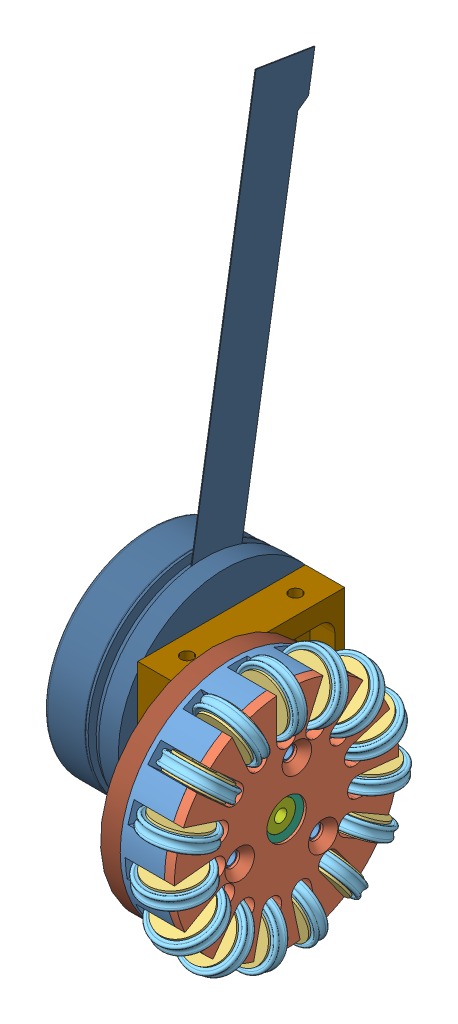
SolidWorks assembly drive_left, configuration Default. Lengths in mm.
Overall size (58.89 137.4 77.93).
70 component instances, 12 part files, 26 mates.
Components (placement in the parent):
- wheel_hub_flat_back-1: wheel_hub_flat_back [Default] at (-31.4027 -2.3485 15.5279) size (9 45.5 45.5)
- wheel_cover-1: wheel_cover [Default] at (-22.4027 -2.3485 15.5279) size (2 45.41 45.5)
- wheel_roller_asm-1: wheel_roller_asm [Default] at (-3.0698 37.2715 -2.2573) x (0.742932 0.669367 0) z (0 0 1) size (12.8 12.8 6)
  - wheel_roller_hub-1: wheel_roller_hub [Default] at (-28.6925 -1.096 17.7852) size (10.4 10.4 3.8)
  - wheel_roller_pin-1: wheel_roller_pin [Default] at (-28.6925 -1.096 14.7852) size (2.5 2.5 6)
  - xring_109-1: xring_109 [Default] at (-28.6925 -1.096 17.7852) size (12.8 12.8 2.6)
- wheel_roller_asm-2: wheel_roller_asm [Default] at (-3.0698 41.0801 15.3952) x (0.742932 0.611497 0.272256) z (0 -0.406737 0.913545) size (12.8 12.8 6)
  - wheel_roller_hub-1: wheel_roller_hub [Default] at (-28.6925 -1.096 17.7852) size (10.4 10.4 3.8)
  - wheel_roller_pin-1: wheel_roller_pin [Default] at (-28.6925 -1.096 14.7852) size (2.5 2.5 6)
  - xring_109-1: xring_109 [Default] at (-28.6925 -1.096 17.7852) size (12.8 12.8 2.6)
- wheel_roller_asm-3: wheel_roller_asm [Default] at (-3.0698 37.3795 33.0707) x (0.742932 0.447894 0.497437) z (0 -0.743145 0.669131) size (12.8 12.8 6)
  - wheel_roller_hub-1: wheel_roller_hub [Default] at (-28.6925 -1.096 17.7852) size (10.4 10.4 3.8)
  - wheel_roller_pin-1: wheel_roller_pin [Default] at (-28.6925 -1.096 14.7852) size (2.5 2.5 6)
  - xring_109-1: xring_109 [Default] at (-28.6925 -1.096 17.7852) size (12.8 12.8 2.6)
- wheel_roller_asm-4: wheel_roller_asm [Default] at (-3.0698 26.8095 47.7129) x (0.742932 0.206846 0.636606) z (0 -0.951057 0.309017) size (12.8 12.8 6)
  - wheel_roller_hub-1: wheel_roller_hub [Default] at (-28.6925 -1.096 17.7852) size (10.4 10.4 3.8)
  - wheel_roller_pin-1: wheel_roller_pin [Default] at (-28.6925 -1.096 14.7852) size (2.5 2.5 6)
  - xring_109-1: xring_109 [Default] at (-28.6925 -1.096 17.7852) size (12.8 12.8 2.6)
- wheel_roller_asm-5: wheel_roller_asm [Default] at (-3.0698 11.1979 56.79) x (0.742932 -0.069968 0.6657) z (0 -0.994522 -0.104528) size (12.8 12.8 6)
  - wheel_roller_hub-1: wheel_roller_hub [Default] at (-28.6925 -1.096 17.7852) size (10.4 10.4 3.8)
  - wheel_roller_pin-1: wheel_roller_pin [Default] at (-28.6925 -1.096 14.7852) size (2.5 2.5 6)
  - xring_109-1: xring_109 [Default] at (-28.6925 -1.096 17.7852) size (12.8 12.8 2.6)
- wheel_roller_asm-6: wheel_roller_asm [Default] at (-3.0698 -6.7561 58.7325) x (0.742932 -0.334684 0.579689) z (0 -0.866025 -0.5) size (12.8 12.8 6)
  - wheel_roller_hub-1: wheel_roller_hub [Default] at (-28.6925 -1.096 17.7852) size (10.4 10.4 3.8)
  - wheel_roller_pin-1: wheel_roller_pin [Default] at (-28.6925 -1.096 14.7852) size (2.5 2.5 6)
  - xring_109-1: xring_109 [Default] at (-28.6925 -1.096 17.7852) size (12.8 12.8 2.6)
- wheel_roller_asm-7: wheel_roller_asm [Default] at (-3.0698 -23.9479 53.2045) x (0.742932 -0.541529 0.393444) z (0 -0.587785 -0.809017) size (12.8 12.8 6)
  - wheel_roller_hub-1: wheel_roller_hub [Default] at (-28.6925 -1.096 17.7852) size (10.4 10.4 3.8)
  - wheel_roller_pin-1: wheel_roller_pin [Default] at (-28.6925 -1.096 14.7852) size (2.5 2.5 6)
  - xring_109-1: xring_109 [Default] at (-28.6925 -1.096 17.7852) size (12.8 12.8 2.6)
- wheel_roller_asm-8: wheel_roller_asm [Default] at (-3.0698 -37.405 41.162) x (0.742932 -0.65474 0.139169) z (0 -0.207912 -0.978148) size (12.8 12.8 6)
  - wheel_roller_hub-1: wheel_roller_hub [Default] at (-28.6925 -1.096 17.7852) size (10.4 10.4 3.8)
  - wheel_roller_pin-1: wheel_roller_pin [Default] at (-28.6925 -1.096 14.7852) size (2.5 2.5 6)
  - xring_109-1: xring_109 [Default] at (-28.6925 -1.096 17.7852) size (12.8 12.8 2.6)
- wheel_roller_asm-9: wheel_roller_asm [Default] at (-3.0698 -44.8005 24.687) x (0.742932 -0.65474 -0.139169) z (0 0.207912 -0.978148) size (12.8 12.8 6)
  - wheel_roller_hub-1: wheel_roller_hub [Default] at (-28.6925 -1.096 17.7852) size (10.4 10.4 3.8)
  - wheel_roller_pin-1: wheel_roller_pin [Default] at (-28.6925 -1.096 14.7852) size (2.5 2.5 6)
  - xring_109-1: xring_109 [Default] at (-28.6925 -1.096 17.7852) size (12.8 12.8 2.6)
- wheel_roller_asm-10: wheel_roller_asm [Default] at (-3.0698 -44.8557 6.6284) x (0.742932 -0.541529 -0.393444) z (0 0.587785 -0.809017) size (12.8 12.8 6)
  - wheel_roller_hub-1: wheel_roller_hub [Default] at (-28.6925 -1.096 17.7852) size (10.4 10.4 3.8)
  - wheel_roller_pin-1: wheel_roller_pin [Default] at (-28.6925 -1.096 14.7852) size (2.5 2.5 6)
  - xring_109-1: xring_109 [Default] at (-28.6925 -1.096 17.7852) size (12.8 12.8 2.6)
- wheel_roller_asm-11: wheel_roller_asm [Default] at (-3.0698 -37.561 -9.8914) x (0.742932 -0.334684 -0.579689) z (0 0.866025 -0.5) size (12.8 12.8 6)
  - wheel_roller_hub-1: wheel_roller_hub [Default] at (-28.6925 -1.096 17.7852) size (10.4 10.4 3.8)
  - wheel_roller_pin-1: wheel_roller_pin [Default] at (-28.6925 -1.096 14.7852) size (2.5 2.5 6)
  - xring_109-1: xring_109 [Default] at (-28.6925 -1.096 17.7852) size (12.8 12.8 2.6)
- wheel_roller_asm-12: wheel_roller_asm [Default] at (-3.0698 -24.1777 -22.016) x (0.742932 -0.069968 -0.6657) z (0 0.994522 -0.104528) size (12.8 12.8 6)
  - wheel_roller_hub-1: wheel_roller_hub [Default] at (-28.6925 -1.096 17.7852) size (10.4 10.4 3.8)
  - wheel_roller_pin-1: wheel_roller_pin [Default] at (-28.6925 -1.096 14.7852) size (2.5 2.5 6)
  - xring_109-1: xring_109 [Default] at (-28.6925 -1.096 17.7852) size (12.8 12.8 2.6)
- wheel_roller_asm-13: wheel_roller_asm [Default] at (-3.0698 -7.02 -27.6489) x (0.742932 0.206846 -0.636606) z (0 0.951057 0.309017) size (12.8 12.8 6)
  - wheel_roller_hub-1: wheel_roller_hub [Default] at (-28.6925 -1.096 17.7852) size (10.4 10.4 3.8)
  - wheel_roller_pin-1: wheel_roller_pin [Default] at (-28.6925 -1.096 14.7852) size (2.5 2.5 6)
  - xring_109-1: xring_109 [Default] at (-28.6925 -1.096 17.7852) size (12.8 12.8 2.6)
- wheel_roller_asm-14: wheel_roller_asm [Default] at (-3.0698 10.9455 -25.8162) x (0.742932 0.447894 -0.497437) z (0 0.743145 0.669131) size (12.8 12.8 6)
  - wheel_roller_hub-1: wheel_roller_hub [Default] at (-28.6925 -1.096 17.7852) size (10.4 10.4 3.8)
  - wheel_roller_pin-1: wheel_roller_pin [Default] at (-28.6925 -1.096 14.7852) size (2.5 2.5 6)
  - xring_109-1: xring_109 [Default] at (-28.6925 -1.096 17.7852) size (12.8 12.8 2.6)
- wheel_roller_asm-15: wheel_roller_asm [Default] at (-3.0698 26.6123 -16.8346) x (0.742932 0.611497 -0.272256) z (0 0.406737 0.913545) size (12.8 12.8 6)
  - wheel_roller_hub-1: wheel_roller_hub [Default] at (-28.6925 -1.096 17.7852) size (10.4 10.4 3.8)
  - wheel_roller_pin-1: wheel_roller_pin [Default] at (-28.6925 -1.096 14.7852) size (2.5 2.5 6)
  - xring_109-1: xring_109 [Default] at (-28.6925 -1.096 17.7852) size (12.8 12.8 2.6)
- MF126ZZ-1: MF126ZZ [Default] at (-21.6027 -2.3485 15.5279) x (-1 0 0) z (0 0.924225 0.381849) size (4 13.6 13.6)
- MF126ZZ-2: MF126ZZ [Default] at (-31.4027 -2.3485 15.5279) size (4 13.6 13.6)
- wheel_rod-1: wheel_rod [Default] at (-21.6027 -2.3485 15.5279) x (-1 0 0) z (0 0.924225 0.381849) size (23 8 8)
- spur_gear-1: spur_gear [Metric - Spur gear 0.5M 20T 20PA 3FW ---S20O8H8L4N] at (-35.4027 2.1015 3.8468) x (1 0 0) z (0 0.642462 0.766317) size (8 10.9 10.9)
- motor_mount_left-1: motor_mount_left [Default] at (-44.6027 -15.7485 21.5279) size (8 32 34)
- EC45fl-200142-1: EC45fl-200142 [Default] at (-44.6027 2.1015 3.8468) x (-1 0 0) z (0 0.158938 0.987289) size (36.9 124.1 43.2)
- internal_gear_70-4: internal_gear_70 [DIN - Internal spur gear 0.5M 70T 20PA 4FW ---S70S45,5OD 1AF] at (-31.4027 -2.3485 15.5279) x (-1 0 0) z (0 -0.994522 -0.104528) size (4 45.5 45.5)
- motor_shaft_extension-1: motor_shaft_extension [Default] at (-55.0027 2.1015 3.8468) x (-1 0 0) z (0 0.167928 -0.985799) size (18.5 4 4)
Mates (geometry in assembly coordinates):
- Width1: width anti-aligned: plane of wheel_hub_flat_back-1 through (-30.4027 12.1015 17.5279) normal (0 0 -1); plane of wheel_hub_flat_back-1 through (-30.4027 20.4015 13.5279) normal (0 0 1); plane of wheel_roller_asm-1/wheel_roller_hub-1 through (-24.5229 18.2173 17.4279) normal (0 0 1); plane of wheel_roller_asm-1/wheel_roller_hub-1 through (-24.9915 18.7374 13.6279) normal (0 0 -1)
- Distance1: distance = 0 mm aligned: plane of wheel_hub_flat_back-1 through (-22.4027 -2.3485 15.5279) normal (1 0 0); cylinder of wheel_roller_asm-1/wheel_roller_pin-1 through (-23.6527 17.2515 18.5279) axis (0 0 -1) radius 1.25
- Distance2: distance = 0 mm anti-aligned: cylinder of wheel_roller_asm-1/wheel_roller_pin-1 through (-23.6527 17.2515 18.5279) axis (0 0 -1) radius 1.25; plane of wheel_hub_flat_back-1 through (-24.9027 18.5015 18.5279) normal (0 -1 0)
- Concentric2: concentric aligned: cylinder of wheel_hub_flat_back-1 through (-22.4027 7.433 13.4488) axis (1 0 0) radius 1.25; cylinder of wheel_cover-1 through (-22.4037 7.433 13.4488) axis (1 0 0) radius 1.5
- Concentric3: concentric aligned: cylinder of wheel_cover-1 through (-22.4037 7.433 13.4488) axis (1 0 0) radius 1.5; cylinder of wheel_hub_flat_back-1 through (-22.4027 7.433 13.4488) axis (1 0 0) radius 1.25
- Coincident1: coincident anti-aligned: plane of wheel_hub_flat_back-1 through (-22.4027 -2.3485 15.5279) normal (1 0 0); plane of wheel_cover-1 through (-22.4027 -2.3485 15.5279) normal (-1 0 0)
- Concentric4: concentric aligned: cylinder of wheel_hub_flat_back-1 through (-22.4027 -2.3485 15.5279) axis (-1 0 0) radius 6.005; cylinder of MF126ZZ-2 through (-31.4027 -2.3485 15.5279) axis (-1 0 0) radius 6
- Coincident2: coincident anti-aligned: plane of wheel_hub_flat_back-1 through (-30.6027 -2.3485 15.5279) normal (-1 0 0); plane of MF126ZZ-2 through (-30.6027 4.4515 15.5279) normal (1 0 0)
- Concentric5: concentric anti-aligned: cylinder of wheel_hub_flat_back-1 through (-22.4027 -2.3485 15.5279) axis (-1 0 0) radius 6.005; cylinder of MF126ZZ-1 through (-21.6027 -2.3485 15.5279) axis (1 0 0) radius 6
- Coincident3: coincident anti-aligned: plane of wheel_hub_flat_back-1 through (-22.4027 -2.3485 15.5279) normal (1 0 0); plane of MF126ZZ-1 through (-22.4027 -4.9451 21.8126) normal (-1 0 0)
- Concentric6: concentric aligned: cylinder of MF126ZZ-1 through (-21.6027 -2.3485 15.5279) axis (1 0 0) radius 3; cylinder of wheel_rod-1 through (-21.6027 -2.3485 15.5279) axis (1 0 0) radius 2.99
- Coincident4: coincident anti-aligned: plane of MF126ZZ-2 through (-31.4027 0.6515 15.5279) normal (-1 0 0); plane of wheel_rod-1 through (-31.4027 -3.8759 19.2248) normal (1 0 0)
- Concentric9: concentric aligned: cylinder of wheel_rod-1 through (-21.6027 -2.3485 15.5279) axis (1 0 0) radius 3; cylinder of motor_mount_left-1 through (-44.6037 -2.3485 15.5279) axis (1 0 0) radius 3
- Concentric10: concentric aligned: cylinder of spur_gear-1 through (-40.4028 2.1015 3.8468) axis (1 0 0) radius 4; cylinder of motor_mount_left-1 through (-44.6037 2.1015 3.8468) axis (1 0 0) radius 6.1
- Coincident8: coincident anti-aligned: plane of wheel_rod-1 through (-36.6027 -3.4941 18.3006) normal (-1 0 0); plane of motor_mount_left-1 through (-36.6027 -15.7485 21.5279) normal (1 0 0)
- Concentric11: concentric aligned: cylinder of motor_mount_left-1 through (-44.6037 2.1015 3.8468) axis (1 0 0) radius 6.1; cylinder of EC45fl-200142-1 through (-44.6027 2.1015 3.8468) axis (1 0 0) radius 6
- Concentric12: concentric aligned: cylinder of motor_mount_left-1 through (-44.6037 6.0175 -6.4325) axis (1 0 0) radius 1.5; cylinder of EC45fl-200142-1 through (-48.6027 6.0175 -6.4325) axis (1 0 0) radius 1.25
- Coincident9: coincident anti-aligned: plane of motor_mount_left-1 through (-44.6027 -15.7485 21.5279) normal (-1 0 0); plane of EC45fl-200142-1 through (-44.6027 2.1015 3.8468) normal (1 0 0)
- Concentric13: concentric aligned: cylinder of spur_gear-1 through (-40.4028 2.1015 3.8468) axis (1 0 0) radius 4; cylinder of EC45fl-200142-1 through (-42.1027 2.1015 3.8468) axis (1 0 0) radius 2
- Parallel1: parallel anti-aligned: plane of motor_mount_left-1 through (-36.6027 -15.7485 21.5279) normal (0 -1 0); plane of assembly through (0 0 0) normal (0 1 0)
- Coincident10: coincident anti-aligned: plane of wheel_hub_flat_back-1 through (-31.4027 -2.3485 15.5279) normal (-1 0 0); plane of internal_gear_70-4 through (-31.4027 14.5584 17.3049) normal (1 0 0)
- Concentric14: concentric aligned: cylinder of wheel_hub_flat_back-1 through (-31.4027 17.9481 11.2137) axis (-1 0 0) radius 0.8; cylinder of internal_gear_70-4 through (-31.4017 17.9481 11.2137) axis (-1 0 0) radius 1
- Concentric15: concentric anti-aligned: cylinder of wheel_hub_flat_back-1 through (-22.4027 -2.3485 15.5279) axis (-1 0 0) radius 22.75; cylinder of internal_gear_70-4 through (-21.4027 -2.3485 15.5279) axis (1 0 0) radius 22.75
- Coincident11: coincident aligned: plane of spur_gear-1 through (-35.4027 2.1015 3.8468) normal (-1 0 0); plane of internal_gear_70-4 through (-35.4027 14.5584 17.3049) normal (-1 0 0)
- Concentric16: concentric aligned: cylinder of EC45fl-200142-1 through (-61.0027 2.1015 3.8468) axis (-1 0 0) radius 1.025; cylinder of motor_shaft_extension-1 through (-73.5027 2.1015 3.8468) axis (-1 0 0) radius 1.25
- Coincident12: coincident anti-aligned: plane of EC45fl-200142-1 through (-61.0027 2.1015 3.8468) normal (-1 0 0); plane of motor_shaft_extension-1 through (-61.0027 3.3337 4.0567) normal (1 0 0)
